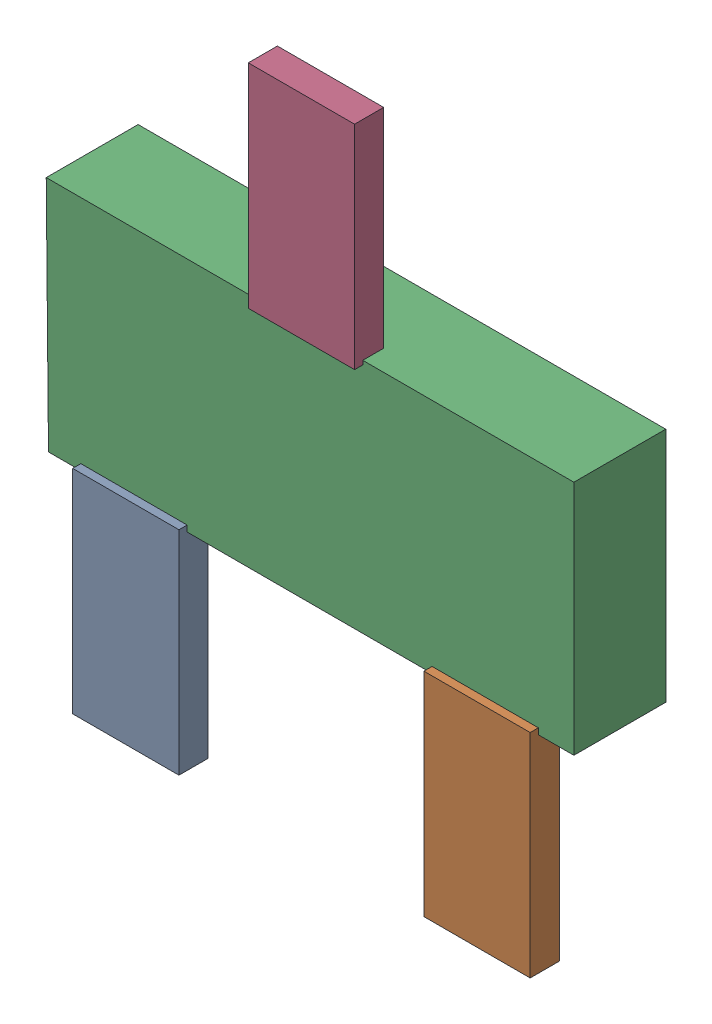
SolidWorks assembly Q2, configuration Default. Lengths in mm.
Overall size (2.9 3.58 0.55).
8 component instances, 2 part files, 0 mates.
Components (placement in the parent):
- 432143248_3-1: 432143248_3 [Default] at (36.8823 18.8492 -0.5715) size (0.58 1.17 0.16)
  - Extruded (36)-1: Extruded (36) [Default] at origin size (0.58 1.17 0.16)
- 432143248_4-1: 432143248_4 [Default] at (38.8127 18.8492 -0.5715) size (0.58 1.17 0.16)
  - Extruded (36)-1: Extruded (36) [Default] at origin size (0.58 1.17 0.16)
- 692618624_1-1: 692618624_1 [Default] at (37.85 20.05 -0.9615) size (2.9 1.3 0.5)
  - Extruded (37)-1: Extruded (37) [Default] at origin size (2.9 1.3 0.5)
- 432143248_5-1: 432143248_5 [Default] at (37.8475 21.2622 -0.5715) size (0.58 1.17 0.16)
  - Extruded (36)-1: Extruded (36) [Default] at origin size (0.58 1.17 0.16)
